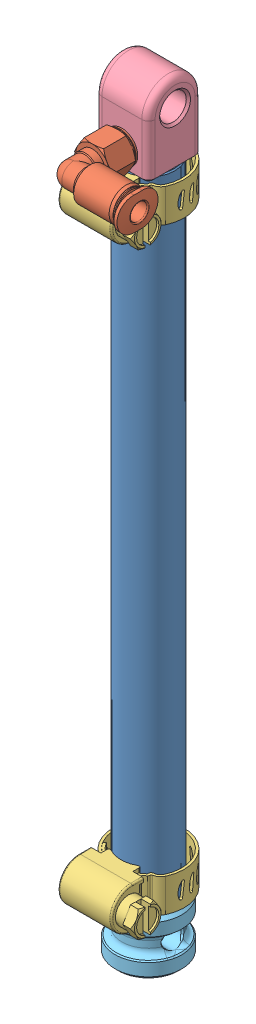
SolidWorks assembly AARL_QR_PN_PA_BR_AN_FL-Flexor, configuration Default. Lengths in mm.
Overall size (24.22 184.15 31.28).
6 component instances, 5 part files, 15 mates.
Components (placement in the parent):
- AARL_QR_PN_PA_BR_AN_FL_001-1: AARL_QR_PN_PA_BR_AN_FL_001 [Resting] at origin size (12.7 152.4 12.7)
- AARL_Puppy_18_02_57_010-QSML-M3-4-1: AARL_Puppy_18_02_57_010-QSML-M3-4 [Default] at (0 80.9625 17.85) x (1 0 0) z (0 0 -1) size (20.32 8 18.9)
- AARL_Puppy_18_02_57_011-5388K140_Hose-Clamp-1: AARL_Puppy_18_02_57_011-5388K140_Hose-Clamp [5388K14] at (0 71.247 0) x (1 0 0) z (0 -1 0) size (19.43 23.71 9.91)
- AARL_Puppy_18_02_57_011-5388K140_Hose-Clamp-2: AARL_Puppy_18_02_57_011-5388K140_Hose-Clamp [5388K14] at (0 -71.247 0) x (1 0 0) z (0 -1 0) size (19.43 23.71 9.91)
- AARL_QR_PN_EP_001-1: AARL_QR_PN_EP_001 [Default] at (0 88.9 0) x (0 0 1) z (-1 0 0) size (12.7 31.75 12.7)
- AARL_QR_PN_EP_002-1: AARL_QR_PN_EP_002 [Default] at (0 -76.2 0) x (-1 0 0) z (0 0 1) size (15.88 25.4 15.88)
Mates (geometry in assembly coordinates):
- Concentric1: concentric aligned: cylinder of AARL_QR_PN_PA_BR_AN_FL_001-1 through (0 11.6086 0) axis (0 1 0) radius 4.7625; cylinder of AARL_QR_PN_EP_001-1 through (0 98.444 0) axis (0 1 0) radius 4.3656
- Coincident1: coincident anti-aligned: plane of AARL_QR_PN_PA_BR_AN_FL_001-1 through (4.7625 76.2 0) normal (0 1 0); plane of AARL_QR_PN_EP_001-1 through (-6.35 76.2 -6.35) normal (0 -1 0)
- Parallel1: parallel aligned: plane of AARL_QR_PN_EP_001-1 through (-6.35 76.2 6.35) normal (0 0 1)
- Concentric2: concentric aligned: cylinder of AARL_Puppy_18_02_57_010-QSML-M3-4-1 through (0 80.9625 6.35) axis (0 0 1) radius 1.5; cylinder of AARL_QR_PN_EP_001-1 through (0 80.9625 6.35) axis (0 0 1) radius 2.0193
- Coincident3: coincident anti-aligned: plane of AARL_Puppy_18_02_57_010-QSML-M3-4-1 through (0 80.9625 6.35) normal (0 0 -1); plane of AARL_QR_PN_EP_001-1 through (-6.35 76.2 6.35) normal (0 0 1)
- Parallel2: parallel anti-aligned: plane of AARL_Puppy_18_02_57_010-QSML-M3-4-1 through (-2.3094 84.9625 13.4056) normal (0 1 0); plane of AARL_QR_PN_EP_001-1 through (-6.35 76.2 -6.35) normal (0 -1 0)
- Concentric3: concentric anti-aligned: cylinder of AARL_QR_PN_PA_BR_AN_FL_001-1 through (0 11.6086 0) axis (0 1 0) radius 4.7625; cylinder of AARL_QR_PN_EP_002-1 through (0 -83.9377 0) axis (0 -1 0) radius 4.3656
- Coincident5: coincident anti-aligned: plane of AARL_QR_PN_PA_BR_AN_FL_001-1 through (6.35 -76.2 0) normal (0 -1 0); plane of AARL_QR_PN_EP_002-1 through (-4.3656 -76.2 0) normal (0 1 0)
- Parallel3: parallel anti-aligned: cylinder of AARL_QR_PN_EP_001-1 through (-6.35 88.9 0) axis (1 0 0) radius 3.175; cylinder of AARL_QR_PN_EP_002-1 through (7.9375 -82.55 0) axis (-1 0 0) radius 2.3813
- Concentric5: concentric aligned: cylinder of AARL_QR_PN_PA_BR_AN_FL_001-1 through (0 11.6086 0) axis (0 1 0) radius 6.35; cylinder of AARL_Puppy_18_02_57_011-5388K140_Hose-Clamp-1 through (0 67.2782 0) axis (0 1 0) radius 7.9375
- Coincident6: coincident aligned: plane of AARL_Puppy_18_02_57_011-5388K140_Hose-Clamp-1 through (6.35 71.247 10.2337) normal (1 0 0); plane of AARL_QR_PN_EP_001-1 through (6.35 88.9 0) normal (1 0 0)
- Coincident7: coincident anti-aligned: plane of AARL_Puppy_18_02_57_011-5388K140_Hose-Clamp-1 through (0 76.2 0) normal (0 1 0); plane of AARL_QR_PN_EP_001-1 through (-6.35 76.2 -6.35) normal (0 -1 0)
- Concentric6: concentric aligned: cylinder of AARL_QR_PN_PA_BR_AN_FL_001-1 through (0 11.6086 0) axis (0 1 0) radius 6.35; cylinder of AARL_Puppy_18_02_57_011-5388K140_Hose-Clamp-2 through (0 -75.2157 0) axis (0 1 0) radius 7.9375
- Coincident8: coincident aligned: plane of AARL_Puppy_18_02_57_011-5388K140_Hose-Clamp-1 through (6.35 71.247 10.2337) normal (1 0 0); plane of AARL_Puppy_18_02_57_011-5388K140_Hose-Clamp-2 through (6.35 -71.247 10.2337) normal (1 0 0)
- Coincident9: coincident anti-aligned: plane of AARL_Puppy_18_02_57_011-5388K140_Hose-Clamp-2 through (0 -76.2 0) normal (0 -1 0); plane of AARL_QR_PN_EP_002-1 through (-4.3656 -76.2 0) normal (0 1 0)
